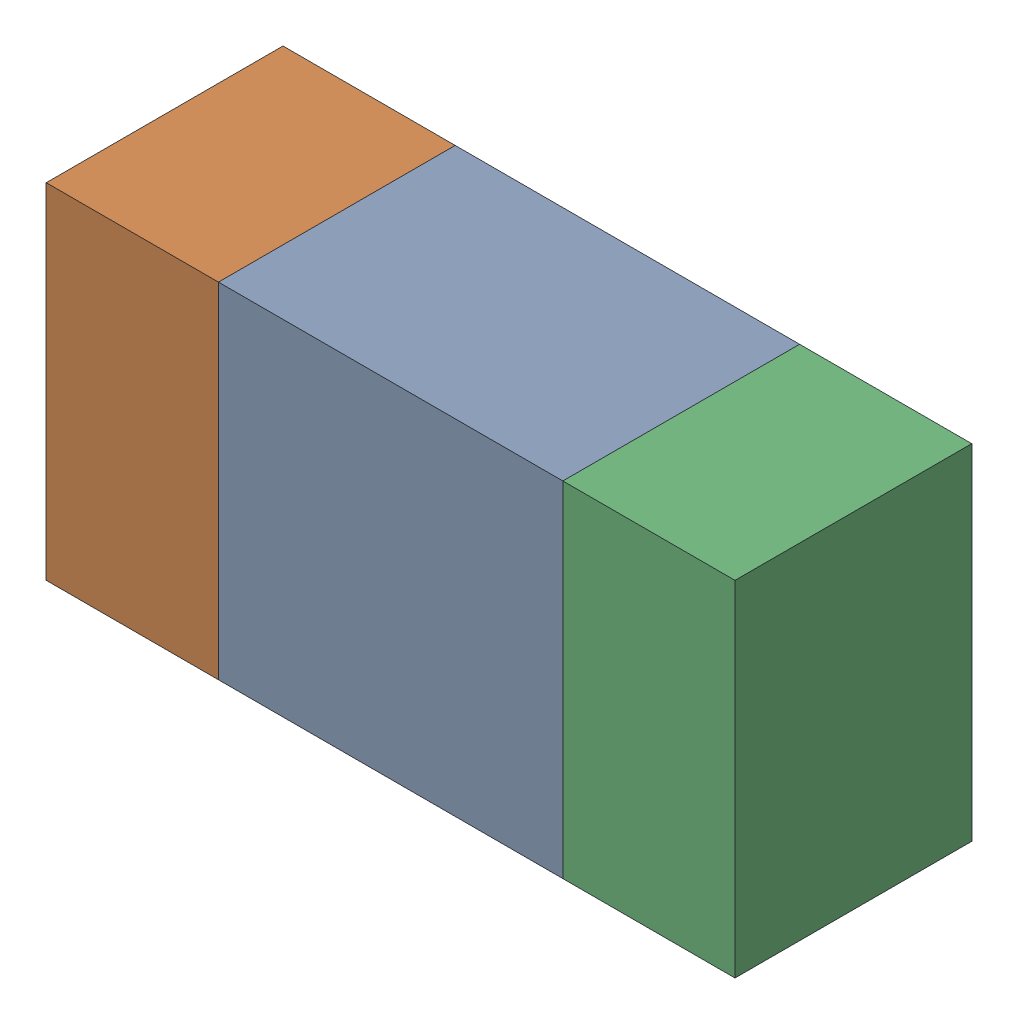
SolidWorks assembly R42, configuration ﾃﾞﾌｫﾙﾄ. Lengths in mm.
Overall size (1.6 0.8 0.55).
6 component instances, 2 part files, 0 mates.
Components (placement in the parent):
- 689261648-1: 689261648 [ﾃﾞﾌｫﾙﾄ] at (57.8 27.5999 0) size (0.8 0.8 0.55)
  - Extruded_33-1: Extruded_33 [ﾃﾞﾌｫﾙﾄ] at origin size (0.8 0.8 0.55)
- 689261512-1: 689261512 [ﾃﾞﾌｫﾙﾄ] at (57.1999 27.5999 0) size (0.4 0.8 0.55)
  - Extruded_32-1: Extruded_32 [ﾃﾞﾌｫﾙﾄ] at origin size (0.4 0.8 0.55)
- 689261512-2: 689261512 [ﾃﾞﾌｫﾙﾄ] at (58.3999 27.5999 0) size (0.4 0.8 0.55)
  - Extruded_32-1: Extruded_32 [ﾃﾞﾌｫﾙﾄ] at origin size (0.4 0.8 0.55)
